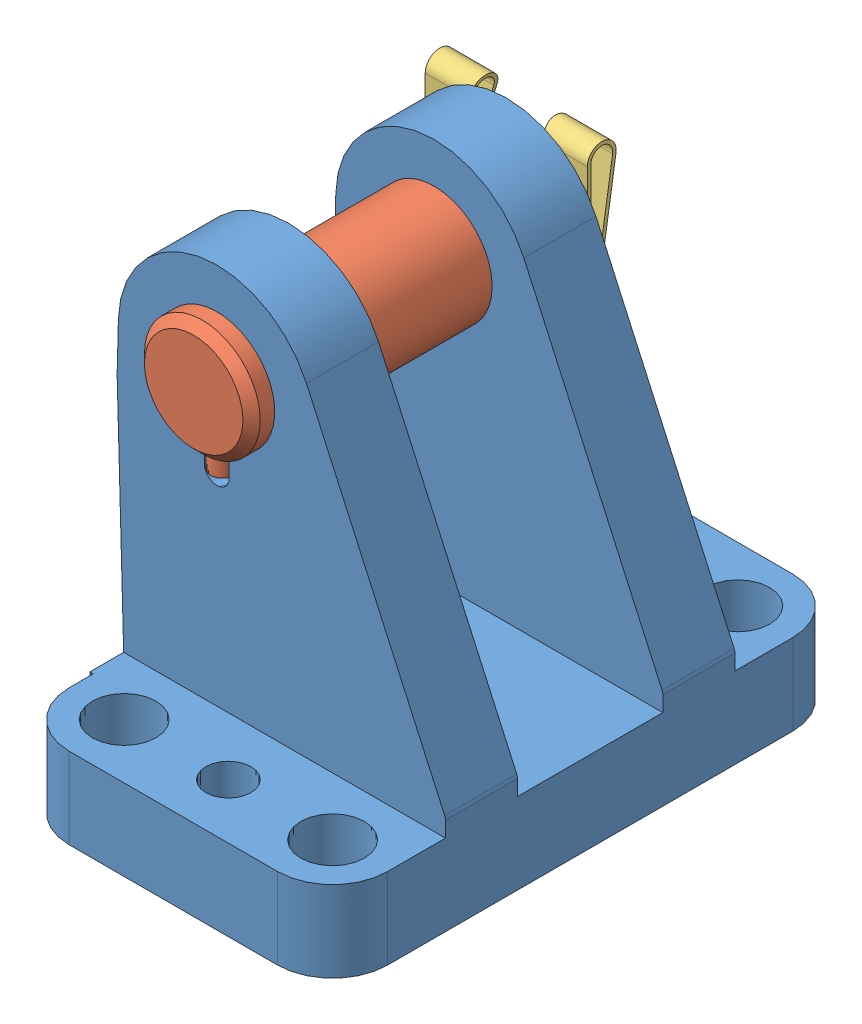
SolidWorks assembly 31765 LBG-80, configuration Default. Lengths in mm.
Overall size (56.72 80 89).
3 component instances, 3 part files, 0 mates.
Components (placement in the parent):
- 31765 LBG-80---(L)-1: 31765 LBG-80---(L) [Default] at origin size (56.72 80 89)
- 373500 BO- 20-049,0-DA-1: 373500 BO- 20-049,0-DA [Default] at (-12 63 -1) x (0 0 -1) z (1 0 0) size (60 24 20)
- 209822 16 SXN 08 VERZINKT_SL-1: 209822 16 SXN 08 VERZINKT_SL [Default] at (-12 63 -25) x (0 0 -1) z (1 0 0) size (5.48 34 28)
